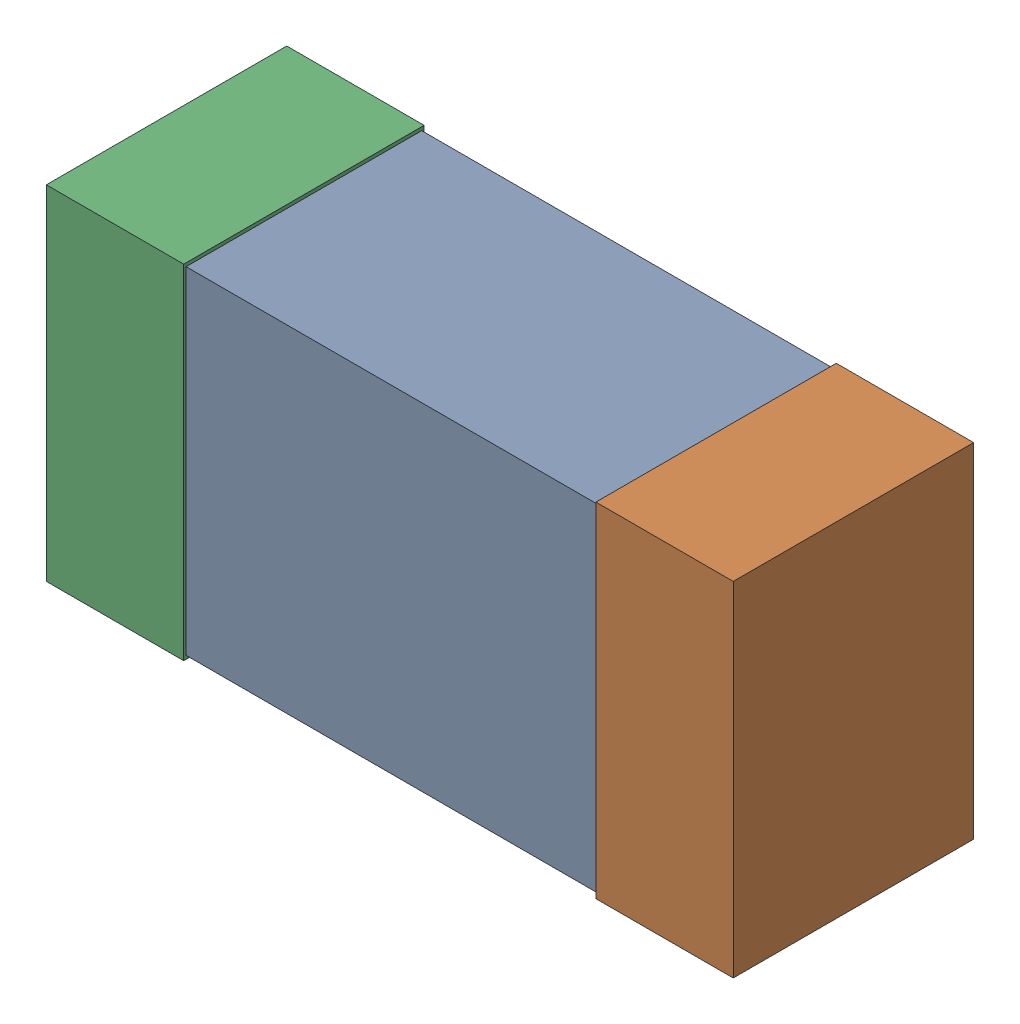
SolidWorks assembly R1, configuration Predeterminado. Lengths in mm.
Overall size (1 0.5 0.35).
4 component instances, 3 part files, 0 mates.
Components (placement in the parent):
- 6074689360-1: 6074689360 [Predeterminado] at (27.5 40 0) size (1 0.5 0.35)
  - body-1-1: body-1 [Predeterminado] at (-0.3 -0.245 0.0035) size (0.6 0.49 0.34)
  - term2-1: term2 [Predeterminado] at (0.3 -0.25 0) size (0.2 0.5 0.35)
  - term1-1: term1 [Predeterminado] at (-0.5 -0.25 0) size (0.2 0.5 0.35)
